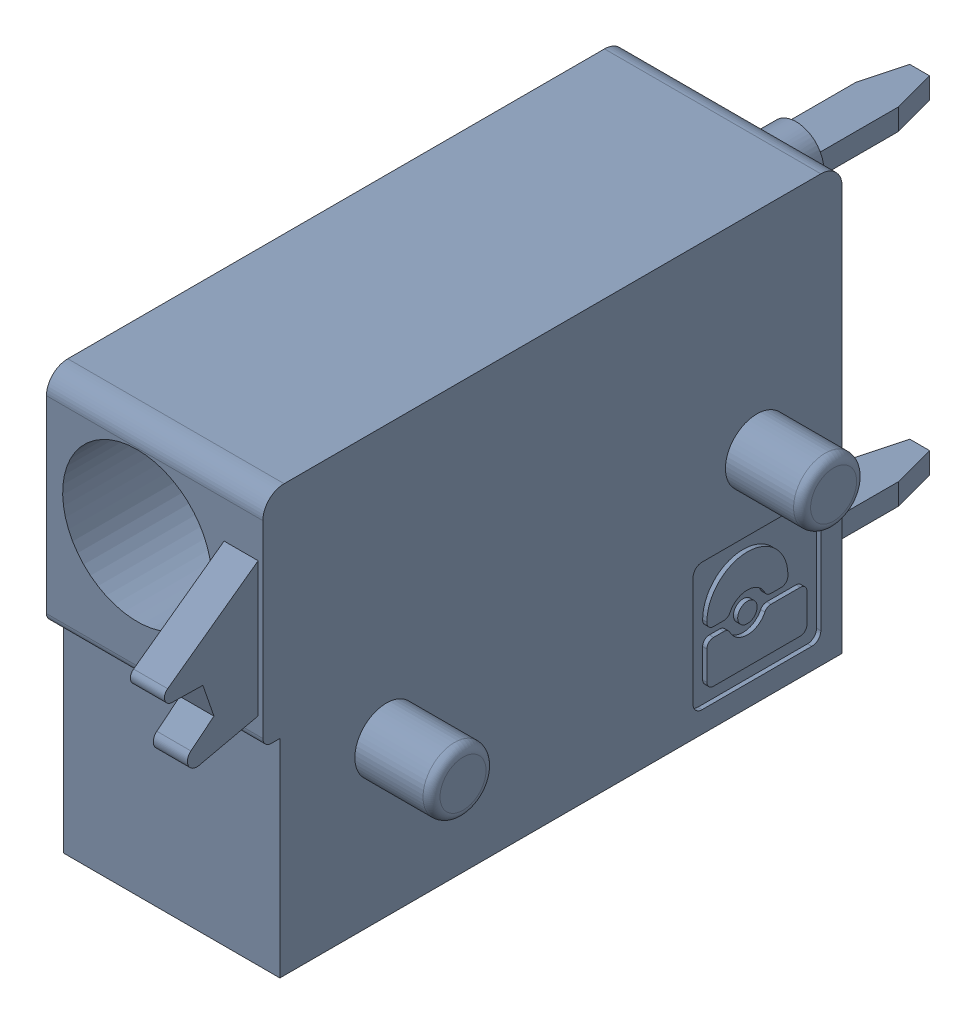
SolidWorks assembly J63, configuration Default. Lengths in mm.
Overall size (6.88 10 19.2).
2 component instances, 1 part files, 0 mates.
Components (placement in the parent):
- 1790348-1: 1790348 [Default] at (182.2451 -7.6199 0) x (0 1 0) z (1 0 0) size (10 19.2 6.88)
  - ffkds-v2-5.08-1: ffkds-v2-5.08 [Default] at (-23.7414 -38.158 -2.54) x (0 -1 0) z (0 0 1) size (19.2 10 6.88)
